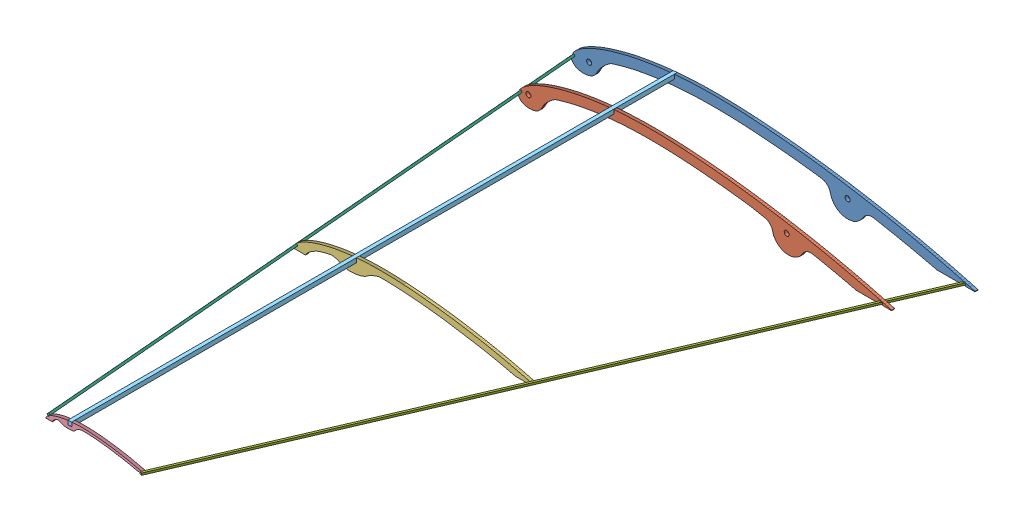
SolidWorks assembly unit05_mainwingL, configuration ﾃﾞﾌｫﾙﾄ. Lengths in mm.
Overall size (400.11 45.91 603.44).
7 component instances, 7 part files, 18 mates.
Components (placement in the parent):
- unit05_mainwing1-1: unit05_mainwing1 [ﾃﾞﾌｫﾙﾄ] at (-466.6327 -212.5638 398.6066) size (400.11 45.91 3)
- unit05_mainwing2-1: unit05_mainwing2 [ﾃﾞﾌｫﾙﾄ] at (-470.5081 -179.0541 458.6066) size (370.1 42.47 3)
- unit05_mainwing3-1: unit05_mainwing3 [ﾃﾞﾌｫﾙﾄ] at (-468.3496 -152.7229 713.6066) size (236.35 23.96 3)
- unit05_mainwing4-1: unit05_mainwing4 [ﾃﾞﾌｫﾙﾄ] at (-504.22 -135.1556 995.6066) size (97.1 9.88 3)
- unit05_mainspar-1: unit05_mainspar [ﾃﾞﾌｫﾙﾄ] at (-360.8252 -120.8753 398.6066) x (0.996195 0.087156 0) z (0 0 1) size (4 4 600)
- unit05_leadingedge-1: unit05_leadingedge [ﾃﾞﾌｫﾙﾄ] at (-458.9956 -152.5455 398.7862) x (0.690567 0.712976 -0.121583) z (0.126374 0.046573 0.990889) size (2 2 604.67)
- unit05_trailingedge-1: unit05_trailingedge [ﾃﾞﾌｫﾙﾄ] at (-71.811 -155.3914 398.9833) x (0.941239 -0.013896 0.337455) z (-0.336511 0.046633 0.940524) size (2 2 640.8)
Mates (geometry in assembly coordinates):
- 一致1: coincident anti-aligned: plane of unit05_mainwing1-1 through (-473.6154 -132.7508 401.6066) normal (-0.087156 0.996195 0); plane of unit05_mainspar-1 through (-362.6433 -123.042 998.6066) normal (0.087156 -0.996195 0)
- 一致2: coincident anti-aligned: plane of unit05_mainwing1-1 through (-355.6606 -202.855 401.6066) normal (0.996195 0.087156 0); plane of unit05_mainspar-1 through (-362.9919 -119.0572 998.6066) normal (-0.996195 -0.087156 0)
- 一致3: coincident aligned: plane of unit05_mainwing1-1 through (-466.6327 -212.5638 398.6066) normal (0 0 -1); plane of unit05_mainspar-1 through (-360.8252 -120.8753 398.6066) normal (0 0 -1)
- 一致4: coincident anti-aligned: plane of unit05_mainwing2-1 through (-474.552 -132.8327 461.6066) normal (-0.087156 0.996195 0); plane of unit05_mainspar-1 through (-362.6433 -123.042 998.6066) normal (0.087156 -0.996195 0)
- 一致5: coincident anti-aligned: plane of unit05_mainwing2-1 through (-358.5995 -169.2634 461.6066) normal (0.996195 0.087156 0); plane of unit05_mainspar-1 through (-362.9919 -119.0572 998.6066) normal (-0.996195 -0.087156 0)
- 一致8: coincident anti-aligned: plane of unit05_mainwing4-1 through (-504.1963 -135.4263 998.6066) normal (-0.087156 0.996195 0); plane of unit05_mainspar-1 through (-362.6433 -123.042 998.6066) normal (0.087156 -0.996195 0)
- 一致9: coincident anti-aligned: plane of unit05_mainwing4-1 through (-358.6822 -122.4227 998.6066) normal (-0.996195 -0.087156 0); plane of unit05_mainspar-1 through (-359.0072 -118.7086 998.6066) normal (0.996195 0.087156 0)
- 一致10: coincident anti-aligned: plane of unit05_mainwing3-1 through (-356.8845 -142.971 716.6066) normal (-0.996195 -0.087156 0); plane of unit05_mainspar-1 through (-359.0072 -118.7086 998.6066) normal (0.996195 0.087156 0)
- 一致12: coincident: line of unit05_mainwing3-1 through (-358.6585 -122.6933 716.6066) axis (0 0 -1); plane of unit05_mainspar-1 through (-362.6433 -123.042 998.6066) normal (0.087156 -0.996195 0)
- 一致13: coincident aligned: plane of unit05_mainwing4-1 through (-504.22 -135.1556 998.6066) normal (0 0 1); plane of unit05_mainspar-1 through (-360.8252 -120.8753 998.6066) normal (0 0 1)
- 距離1: distance = 60 mm aligned: plane of unit05_mainwing1-1 through (-466.6327 -212.5638 398.6066) normal (0 0 -1); plane of unit05_mainwing2-1 through (-470.5081 -179.0541 458.6066) normal (0 0 -1)
- 距離2: distance = 255 mm aligned: plane of unit05_mainwing2-1 through (-470.5081 -179.0541 458.6066) normal (0 0 -1); plane of unit05_mainwing3-1 through (-468.3496 -152.7229 713.6066) normal (0 0 -1)
- 一致16: coincident: line of unit05_mainwing1-1 through (-457.5929 -152.5321 401.6066) axis (0 0 -1); point of unit05_leadingedge-1
- 一致19: coincident: line of unit05_mainwing4-1 through (-382.5594 -125.7965 998.6066) axis (0 0 -1); point of unit05_leadingedge-1
- 一致20: coincident: line of unit05_mainwing1-1 through (-457.5929 -152.5321 398.6066) axis (-0.707107 -0.707107 0); point of unit05_leadingedge-1
- 一致22: coincident: line of unit05_mainwing1-1 through (-72.7234 -154.3787 398.6066) axis (1 0 0); point of unit05_trailingedge-1
- 一致23: coincident: line of unit05_mainwing1-1 through (-72.7234 -156.5229 398.6066) axis (0 1 0); point of unit05_trailingedge-1
- 一致24: coincident: point of unit05_mainwing4-1; plane of unit05_trailingedge-1 through (-288.3594 -124.4963 1001.2946) normal (-0.941239 0.013896 -0.337455)
